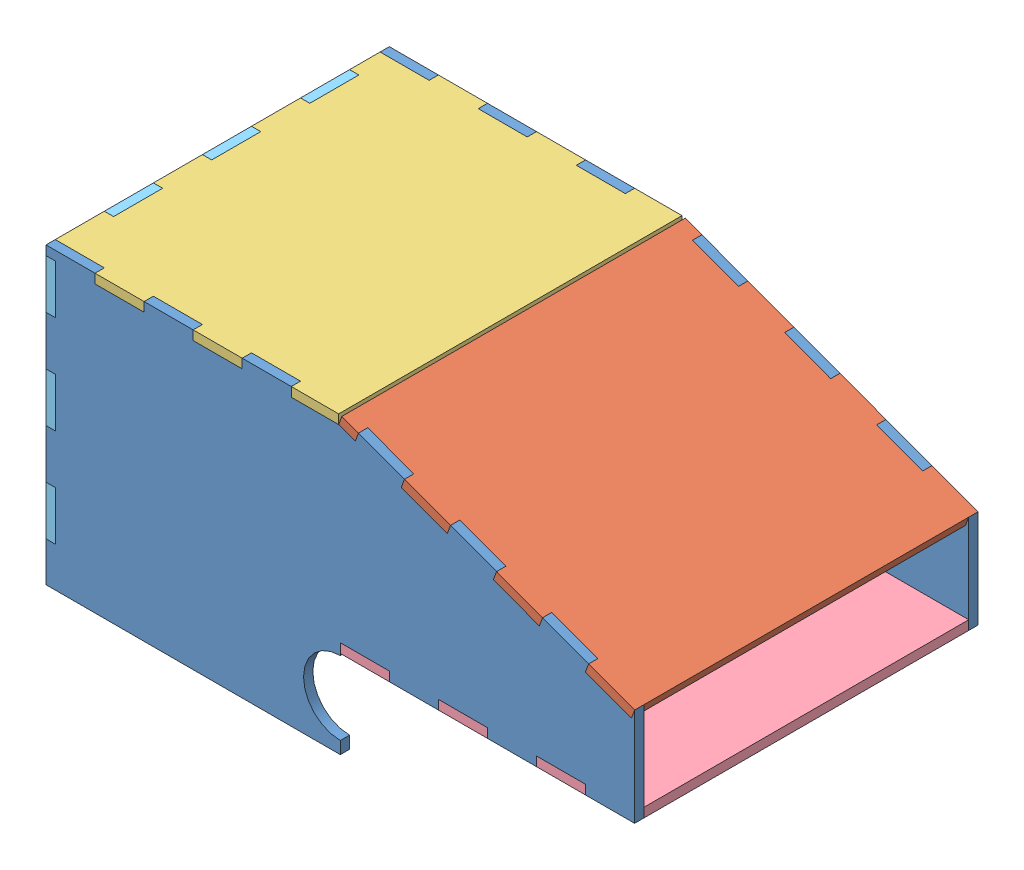
SolidWorks assembly Dashboard, configuration Default. Lengths in mm.
Overall size (152.4 76.2 88.9).
6 component instances, 5 part files, 19 mates.
Components (placement in the parent):
- side-1: side [Default] at (48.7615 71.2746 126.8767) size (152.4 76.2 2.4)
- side-2: side [Default] at (48.7615 71.2746 40.3767) size (152.4 76.2 2.4)
- Part3^Dashboard-1: Part3^Dashboard [Default] at (68.5446 124.9212 40.3767) x (0.938238 -0.345991 0) z (0.345991 0.938238 0) size (80.79 88.9 2.4) (virtual)
- Part4^Dashboard-1: Part4^Dashboard [Default] at (48.7615 132.3746 126.8767) x (1 0 0) z (0 1 0) size (75.77 88.9 2.4) (virtual)
- Part5^Dashboard-1: Part5^Dashboard [Default] at (48.7615 83.6746 126.8767) x (-1 0 0) z (0 -1 0) size (76.2 88.9 2.4) (virtual)
- Part6^Dashboard-1: Part6^Dashboard [Default] at (-25.0385 71.2746 40.3767) x (0 0 1) z (-1 0 0) size (88.9 76.2 2.4) (virtual)
Mates (geometry in assembly coordinates):
- Coincident1: coincident aligned: plane of side-1 through (124.9615 106.6746 129.2767) normal (1 0 0); plane of side-2 through (124.9615 106.6746 42.7767) normal (1 0 0)
- Coincident2: coincident aligned: plane of side-1 through (124.1312 104.4228 129.2767) normal (0.345991 0.938238 0); plane of side-2 through (124.1312 104.4228 42.7767) normal (0.345991 0.938238 0)
- Distance1: distance = 88.9 mm anti-aligned: plane of side-1 through (48.7615 71.2746 129.2767) normal (0 0 1); plane of side-2 through (48.7615 71.2746 40.3767) normal (0 0 -1)
- InPlace1: in place: plane of ? through (52.6374 130.7873 30.0767) normal (0.345991 0.938238 0); plane of ? through (48.7576 132.218 0) normal (0.345991 0.938238 0); moOrthogonalPlaneRef_w of ? through (52.6374 130.7873 30.0767) normal (0.345991 0.938238 0); plane of ? through (48.7576 132.218 0) normal (0 0 -1); plane of ? through (52.6374 130.7873 30.0767) normal (0.345991 0.938238 0); plane of ? through (48.7576 132.218 0) normal (0.938238 -0.345991 0); plane of side-2 through (52.6374 130.7873 42.7767) normal (0.345991 0.938238 0); unknown of Part3^Dashboard-1
- Coincident4: coincident aligned: plane of assembly through (52.6374 130.7873 42.7767) normal (0.345991 0.938238 0)
- Coincident5: coincident aligned: moOrthogonalPlaneRef_w of side-2 through (68.5446 124.9212 40.3767) normal (0 0 -1); plane of Part3^Dashboard-1 through (68.5446 124.9212 40.3767) normal (0 0 -1)
- Coincident6: coincident anti-aligned: moOrthogonalPlaneRef_w of side-2 through (68.5446 124.9212 40.3767) normal (-0.938238 0.345991 0); plane of Part3^Dashboard-1 through (68.5446 124.9212 40.3767) normal (0.938238 -0.345991 0)
- InPlace2: in place: plane of side-1 through (36.0615 132.3746 129.2767) normal (0 1 0); plane of ? through (0 132.3746 0) normal (0 1 0); plane of side-1 through (36.0615 132.3746 129.2767) normal (0 1 0); plane of ? through (0 132.3746 0) normal (0 0 -1); plane of side-1 through (36.0615 132.3746 129.2767) normal (0 1 0); plane of ? through (0 132.3746 0) normal (1 0 0); plane of side-1 through (36.0615 132.3746 129.2767) normal (0 1 0); unknown of Part4^Dashboard-1
- Coincident7: coincident aligned: plane of side-1; plane of Part4^Dashboard-1
- Coincident8: coincident aligned: moOrthogonalPlaneRef_w of side-1 through (48.7615 132.3746 126.8767) normal (0 0 -1); plane of Part4^Assem1-1 through (48.7615 132.3746 126.8767) normal (0 0 -1)
- Coincident9: coincident anti-aligned: moOrthogonalPlaneRef_w of side-1 through (48.7615 132.3746 126.8767) normal (-1 0 0); plane of Part4^Assem1-1 through (48.7615 132.3746 126.8767) normal (1 0 0)
- InPlace3: in place: plane of side-1 through (99.5615 83.6746 129.2767) normal (0 -1 0); plane of ? through (0 83.6746 0) normal (0 -1 0); plane of side-1 through (99.5615 83.6746 129.2767) normal (0 -1 0); plane of ? through (0 83.6746 0) normal (0 0 -1); plane of side-1 through (99.5615 83.6746 129.2767) normal (0 -1 0); plane of ? through (0 83.6746 0) normal (-1 0 0); plane of side-1 through (99.5615 83.6746 129.2767) normal (0 -1 0); unknown of Part5^Dashboard-1
- Coincident10: coincident aligned: plane of side-1; plane of Part5^Dashboard-1
- Coincident11: coincident aligned: moOrthogonalPlaneRef_w of side-1 through (48.7615 83.6746 126.8767) normal (0 0 -1); plane of Part5^Dashboard-1 through (48.7615 83.6746 126.8767) normal (0 0 -1)
- Coincident12: coincident anti-aligned: moOrthogonalPlaneRef_w of side-1 through (48.7615 83.6746 126.8767) normal (1 0 0); plane of Part5^Dashboard-1 through (48.7615 83.6746 126.8767) normal (-1 0 0)
- InPlace4: in place: plane of side-2 through (-25.0385 132.3746 42.7767) normal (-1 0 0); plane of ? through (-25.0385 0 0) normal (-1 0 0); plane of side-2 through (-25.0385 132.3746 42.7767) normal (-1 0 0); plane of ? through (-25.0385 0 0) normal (0 1 0); plane of side-2 through (-25.0385 132.3746 42.7767) normal (-1 0 0); plane of ? through (-25.0385 0 0) normal (0 0 1); plane of side-2 through (-25.0385 132.3746 42.7767) normal (-1 0 0); unknown of Part6^Dashboard-1
- Coincident13: coincident aligned: plane of side-2; plane of Part6^Dashboard-1
- Coincident14: coincident aligned: moOrthogonalPlaneRef_w of side-2 through (-25.0385 71.2746 40.3767) normal (0 1 0); plane of Part6^Dashboard-1 through (-25.0385 71.2746 40.3767) normal (0 1 0)
- Coincident15: coincident anti-aligned: moOrthogonalPlaneRef_w of side-2 through (-25.0385 71.2746 40.3767) normal (0 0 -1); plane of Part6^Dashboard-1 through (-25.0385 71.2746 40.3767) normal (0 0 1)
